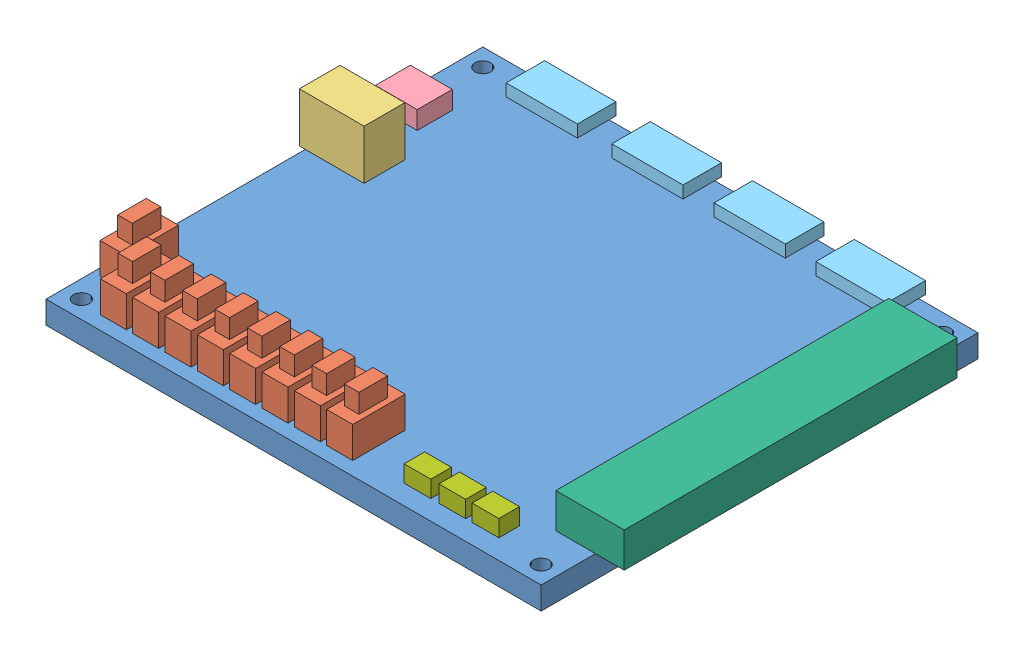
SolidWorks assembly FPGA Assembly, configuration Default. Lengths in mm.
Overall size (117.1 16.1 98.05).
20 component instances, 7 part files, 58 mates.
Components (placement in the parent):
- GreenRect-1: GreenRect [Default] at (-22.5019 45.3504 125.4387) size (109.45 5 96.55)
- Switch-1: Switch [Default] at (-20.8619 50.3504 115.1387) size (5.75 11.1 11.6)
- PowerThing-1: PowerThing [Default] at (-23.8019 50.3504 68.1387) size (14.31 10.95 9)
- USBPort-1: USBPort [Default] at (-23.0019 50.3504 52.1387) size (9.25 4 7.75)
- SixPinHeader-1: SixPinHeader [Default] at (-10.3419 50.3504 35.8887) size (15.75 2.7 8.5)
- SixPinHeader-2: SixPinHeader [Default] at (12.9981 50.3504 35.8887) size (15.75 2.7 8.5)
- SixPinHeader-3: SixPinHeader [Default] at (35.6081 50.3504 35.8887) size (15.75 2.7 8.5)
- SixPinHeader-4: SixPinHeader [Default] at (58.0981 50.3504 35.8887) size (15.75 2.7 8.5)
- J1Header-1: J1Header [Default] at (78.1981 50.3504 113.4387) size (15.1 7.7 73.6)
- Button-2: Button [Default] at (67.3381 50.3504 121.0887) size (5.9 3.7 4.55)
- Button-4: Button [Default] at (59.9981 50.3504 121.0887) size (5.9 3.7 4.55)
- Button-5: Button [Default] at (52.2981 50.3504 121.0887) size (5.9 3.7 4.55)
- Switch-2: Switch [Default] at (-13.5019 50.3504 122.4387) size (5.75 11.1 11.6)
- Switch-3: Switch [Default] at (-6.3519 50.3504 122.4387) size (5.75 11.1 11.6)
- Switch-4: Switch [Default] at (7.9481 50.3504 122.4387) size (5.75 11.1 11.6)
- Switch-5: Switch [Default] at (15.0981 50.3504 122.4387) size (5.75 11.1 11.6)
- Switch-6: Switch [Default] at (22.2481 50.3504 122.4387) size (5.75 11.1 11.6)
- Switch-7: Switch [Default] at (0.7981 50.3504 122.4387) size (5.75 11.1 11.6)
- Switch-9: Switch [Default] at (36.5481 50.3504 122.4387) size (5.75 11.1 11.6)
- Switch-10: Switch [Default] at (29.3981 50.3504 122.4387) size (5.75 11.1 11.6)
Mates (geometry in assembly coordinates):
- Coincident2: coincident anti-aligned: plane of GreenRect-1 through (-22.5019 50.3504 125.4387) normal (0 1 0); plane of Switch-1 through (-20.8619 50.3504 115.1387) normal (0 -1 0)
- Distance2: distance = 10.3 mm: line of Switch-1 through (-20.8619 50.3504 115.1387) axis (1 0 0); line of GreenRect-1 through (-22.5019 50.3504 125.4387) axis (1 0 0)
- Distance3: distance = 1.64 mm: line of Switch-1 through (-20.8619 50.3504 103.5387) axis (0 0 1); line of GreenRect-1 through (-22.5019 50.3504 28.8887) axis (0 0 1)
- Coincident6: coincident anti-aligned: plane of GreenRect-1 through (-22.5019 50.3504 125.4387) normal (0 1 0); plane of PowerThing-1 through (-23.8019 50.3504 68.1387) normal (0 -1 0)
- Distance4: distance = 57.3 mm: line of PowerThing-1 through (-23.8019 50.3504 68.1387) axis (1 0 0); line of GreenRect-1 through (-22.5019 50.3504 125.4387) axis (1 0 0)
- Distance5: distance = 1.3 mm: line of PowerThing-1 through (-23.8019 50.3504 59.1387) axis (0 0 1); line of GreenRect-1 through (-22.5019 50.3504 28.8887) axis (0 0 1)
- Coincident9: coincident anti-aligned: plane of GreenRect-1 through (-22.5019 50.3504 125.4387) normal (0 1 0); plane of USBPort-1 through (-23.0019 50.3504 52.1387) normal (0 -1 0)
- Distance6: distance = 73.3 mm: line of USBPort-1 through (-23.0019 50.3504 52.1387) axis (1 0 0); line of GreenRect-1 through (-22.5019 50.3504 125.4387) axis (1 0 0)
- Distance7: distance = 0.5 mm: line of USBPort-1 through (-23.0019 50.3504 44.3887) axis (0 0 1); line of GreenRect-1 through (-22.5019 50.3504 28.8887) axis (0 0 1)
- Coincident14: coincident anti-aligned: plane of SixPinHeader-1 through (-10.3419 50.3504 35.8887) normal (0 -1 0); plane of GreenRect-1 through (-22.5019 50.3504 125.4387) normal (0 1 0)
- Coincident15: coincident anti-aligned: plane of GreenRect-1 through (-22.5019 50.3504 125.4387) normal (0 1 0); plane of SixPinHeader-2 through (12.9981 50.3504 35.8887) normal (0 -1 0)
- Coincident16: coincident anti-aligned: plane of GreenRect-1 through (-22.5019 50.3504 125.4387) normal (0 1 0); plane of SixPinHeader-3 through (35.6081 50.3504 35.8887) normal (0 -1 0)
- Coincident17: coincident anti-aligned: plane of GreenRect-1 through (-22.5019 50.3504 125.4387) normal (0 1 0); plane of SixPinHeader-4 through (58.0981 50.3504 35.8887) normal (0 -1 0)
- Distance8: distance = 12.16 mm: line of SixPinHeader-1 through (-10.3419 50.3504 27.3887) axis (0 0 1); line of GreenRect-1 through (-22.5019 50.3504 28.8887) axis (0 0 1)
- Distance9: distance = 1.5 mm: line of SixPinHeader-1 through (5.4081 50.3504 27.3887) axis (-1 0 0); line of GreenRect-1 through (86.9481 50.3504 28.8887) axis (-1 0 0)
- Distance10: distance = 1.5 mm: line of SixPinHeader-2 through (28.7481 50.3504 27.3887) axis (-1 0 0); line of GreenRect-1 through (86.9481 50.3504 28.8887) axis (-1 0 0)
- Distance11: distance = 1.5 mm: line of SixPinHeader-3 through (51.3581 50.3504 27.3887) axis (-1 0 0); line of GreenRect-1 through (86.9481 50.3504 28.8887) axis (-1 0 0)
- Distance12: distance = 1.5 mm: line of SixPinHeader-4 through (73.8481 50.3504 27.3887) axis (-1 0 0); line of GreenRect-1 through (86.9481 50.3504 28.8887) axis (-1 0 0)
- Distance13: distance = 35.5 mm: line of SixPinHeader-2 through (12.9981 50.3504 27.3887) axis (0 0 1); line of GreenRect-1 through (-22.5019 50.3504 28.8887) axis (0 0 1)
- Distance14: distance = 58.11 mm: line of SixPinHeader-3 through (35.6081 50.3504 27.3887) axis (0 0 1); line of GreenRect-1 through (-22.5019 50.3504 28.8887) axis (0 0 1)
- Distance15: distance = 80.6 mm: line of SixPinHeader-4 through (58.0981 50.3504 27.3887) axis (0 0 1); line of GreenRect-1 through (-22.5019 50.3504 28.8887) axis (0 0 1)
- Coincident26: coincident anti-aligned: plane of GreenRect-1 through (-22.5019 50.3504 125.4387) normal (0 1 0); plane of J1Header-1 through (78.1981 50.3504 113.4387) normal (0 -1 0)
- Distance16: distance = 100.7 mm: line of J1Header-1 through (78.1981 50.3504 39.8387) axis (0 0 1); line of GreenRect-1 through (-22.5019 50.3504 28.8887) axis (0 0 1)
- Distance17: distance = 12 mm: line of J1Header-1 through (78.1981 50.3504 113.4387) axis (1 0 0); line of GreenRect-1 through (-22.5019 50.3504 125.4387) axis (1 0 0)
- Coincident30: coincident anti-aligned: plane of GreenRect-1 through (-22.5019 50.3504 125.4387) normal (0 1 0); plane of Button-5 through (52.2981 50.3504 121.0887) normal (0 -1 0)
- Coincident31: coincident anti-aligned: plane of GreenRect-1 through (-22.5019 50.3504 125.4387) normal (0 1 0); plane of Button-4 through (59.9981 50.3504 121.0887) normal (0 -1 0)
- Coincident32: coincident anti-aligned: plane of GreenRect-1 through (-22.5019 50.3504 125.4387) normal (0 1 0); plane of Button-2 through (67.3381 50.3504 121.0887) normal (0 -1 0)
- Distance18: distance = 89.84 mm: line of Button-2 through (67.3381 50.3504 116.5387) axis (0 0 1); line of GreenRect-1 through (-22.5019 50.3504 28.8887) axis (0 0 1)
- Distance19: distance = 82.5 mm: line of Button-4 through (59.9981 50.3504 116.5387) axis (0 0 1); line of GreenRect-1 through (-22.5019 50.3504 28.8887) axis (0 0 1)
- Distance21: distance = 74.8 mm: line of Button-5 through (52.2981 50.3504 116.5387) axis (0 0 1); line of GreenRect-1 through (-22.5019 50.3504 28.8887) axis (0 0 1)
- Distance22: distance = 4.35 mm: line of Button-2 through (67.3381 50.3504 121.0887) axis (1 0 0); line of GreenRect-1 through (-22.5019 50.3504 125.4387) axis (1 0 0)
- Distance23: distance = 4.35 mm: line of Button-4 through (59.9981 50.3504 121.0887) axis (1 0 0); line of GreenRect-1 through (-22.5019 50.3504 125.4387) axis (1 0 0)
- Distance24: distance = 4.35 mm: line of Button-5 through (52.2981 50.3504 121.0887) axis (1 0 0); line of GreenRect-1 through (-22.5019 50.3504 125.4387) axis (1 0 0)
- Coincident42: coincident anti-aligned: plane of GreenRect-1 through (-22.5019 50.3504 125.4387) normal (0 1 0); plane of Switch-2 through (-13.5019 50.3504 122.4387) normal (0 -1 0)
- Coincident43: coincident anti-aligned: plane of GreenRect-1 through (-22.5019 50.3504 125.4387) normal (0 1 0); plane of Switch-3 through (-6.3519 50.3504 122.4387) normal (0 -1 0)
- Coincident44: coincident anti-aligned: plane of GreenRect-1 through (-22.5019 50.3504 125.4387) normal (0 1 0); plane of Switch-7 through (0.7981 50.3504 122.4387) normal (0 -1 0)
- Coincident45: coincident anti-aligned: plane of GreenRect-1 through (-22.5019 50.3504 125.4387) normal (0 1 0); plane of Switch-4 through (7.9481 50.3504 122.4387) normal (0 -1 0)
- Coincident46: coincident anti-aligned: plane of GreenRect-1 through (-22.5019 50.3504 125.4387) normal (0 1 0); plane of Switch-5 through (15.0981 50.3504 122.4387) normal (0 -1 0)
- Coincident47: coincident anti-aligned: plane of GreenRect-1 through (-22.5019 50.3504 125.4387) normal (0 1 0); plane of Switch-6 through (22.2481 50.3504 122.4387) normal (0 -1 0)
- Distance26: distance = 3 mm: line of Switch-2 through (-13.5019 50.3504 122.4387) axis (1 0 0); line of GreenRect-1 through (-22.5019 50.3504 125.4387) axis (1 0 0)
- Distance27: distance = 3 mm: line of Switch-3 through (-6.3519 50.3504 122.4387) axis (1 0 0); line of GreenRect-1 through (-22.5019 50.3504 125.4387) axis (1 0 0)
- Distance28: distance = 3 mm: line of Switch-7 through (0.7981 50.3504 122.4387) axis (1 0 0); line of GreenRect-1 through (-22.5019 50.3504 125.4387) axis (1 0 0)
- Distance29: distance = 3 mm: line of Switch-4 through (7.9481 50.3504 122.4387) axis (1 0 0); line of GreenRect-1 through (-22.5019 50.3504 125.4387) axis (1 0 0)
- Distance30: distance = 3 mm: line of Switch-5 through (15.0981 50.3504 122.4387) axis (1 0 0); line of GreenRect-1 through (-22.5019 50.3504 125.4387) axis (1 0 0)
- Distance31: distance = 3 mm: line of Switch-6 through (22.2481 50.3504 122.4387) axis (1 0 0); line of GreenRect-1 through (-22.5019 50.3504 125.4387) axis (1 0 0)
- Distance32: distance = 9 mm: line of Switch-2 through (-13.5019 50.3504 110.8387) axis (0 0 1); line of GreenRect-1 through (-22.5019 50.3504 28.8887) axis (0 0 1)
- Distance33: distance = 1.4 mm: line of Switch-3 through (-6.3519 50.3504 110.8387) axis (0 0 1); line of Switch-2 through (-7.7519 50.3504 122.4387) axis (0 0 -1)
- Distance34: distance = 1.4 mm: line of Switch-7 through (0.7981 50.3504 110.8387) axis (0 0 1); line of Switch-3 through (-0.6019 50.3504 122.4387) axis (0 0 -1)
- Distance35: distance = 1.4 mm: line of Switch-4 through (7.9481 50.3504 110.8387) axis (0 0 1); line of Switch-7 through (6.5481 50.3504 122.4387) axis (0 0 -1)
- Distance36: distance = 1.4 mm: line of Switch-5 through (15.0981 50.3504 110.8387) axis (0 0 1); line of Switch-4 through (13.6981 50.3504 122.4387) axis (0 0 -1)
- Distance37: distance = 1.4 mm: line of Switch-6 through (22.2481 50.3504 110.8387) axis (0 0 1); line of Switch-5 through (20.8481 50.3504 122.4387) axis (0 0 -1)
- Coincident49: coincident anti-aligned: plane of GreenRect-1 through (-22.5019 50.3504 125.4387) normal (0 1 0); plane of Switch-9 through (36.5481 50.3504 120.5675) normal (0 -1 0)
- Distance39: distance = 1.4 mm anti-aligned: plane of Switch-6 through (27.9981 57.2504 122.4387) normal (1 0 0); plane of Switch-10 through (29.3981 57.2504 122.4387) normal (-1 0 0)
- Coincident53: coincident anti-aligned: plane of GreenRect-1 through (-22.5019 50.3504 125.4387) normal (0 1 0); plane of Switch-10 through (29.3981 50.3504 122.4387) normal (0 -1 0)
- Coincident54: coincident aligned: plane of Switch-6 through (22.2481 57.2504 122.4387) normal (0 0 1); plane of Switch-10 through (29.3981 57.2504 122.4387) normal (0 0 1)
- Coincident56: coincident anti-aligned: plane of GreenRect-1 through (-22.5019 50.3504 125.4387) normal (0 1 0); plane of Switch-9 through (36.5481 50.3504 122.4387) normal (0 -1 0)
- Distance40: distance = 1.4 mm anti-aligned: plane of Switch-10 through (35.1481 57.2504 122.4387) normal (1 0 0); plane of Switch-9 through (36.5481 57.2504 122.4387) normal (-1 0 0)
- Coincident58: coincident aligned: plane of Switch-9 through (36.5481 57.2504 122.4387) normal (0 0 1); plane of Switch-10 through (29.3981 57.2504 122.4387) normal (0 0 1)
